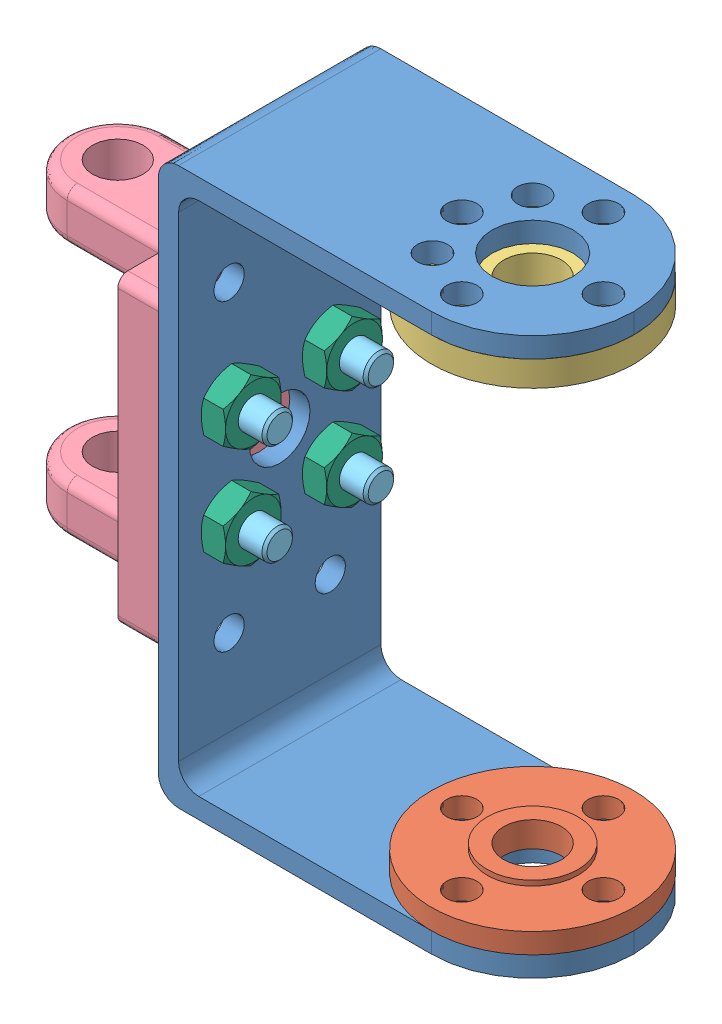
SolidWorks assembly moteur-bras-v2, configuration Défaut. Lengths in mm.
Overall size (56.6 55 20).
12 component instances, 6 part files, 28 mates.
Components (placement in the parent):
- moteur-support-mobile-v2-1: moteur-support-mobile-v2 [Défaut] at (18.386 -2.2808 45) size (37 55 20)
- moteur-platine_libre-1: moteur-platine_libre [Défaut] at (8.386 -27.7808 55) x (1 0 0) z (0 1 0) size (20 20 2.5)
- moteur-platine_moteur-1: moteur-platine_moteur [Défaut] at (8.386 23.2192 55) x (1 0 0) z (0 -1 0) size (20 20 4.5)
- support-fourchette-chc_m3-1: support-fourchette-chc_m3 [Défaut] at (-32.614 -2.2808 55) x (0 1 0) z (0 0 1) size (30 19.6 20)
- vis-chc-1: vis-chc [Vis CHC M3x8] at (-19.614 2.7192 50) x (0 0.164744 0.986336) z (0 -0.986336 0.164744) size (5.5 11 5.5)
- ecrou-h-1: ecrou-h [6012 HU M3] at (-16.614 2.7192 50) x (0 0.866025 0.5) z (0 -0.5 0.866025) size (5.5 2.4 6.35)
- ecrou-h-2: ecrou-h [6012 HU M3] at (-14.214 2.7192 60) x (0 -0.866025 -0.5) z (0 -0.5 0.866025) size (5.5 2.4 6.35)
- ecrou-h-3: ecrou-h [6012 HU M3] at (-14.214 -7.2808 50) x (0 -0.866025 -0.5) z (0 -0.5 0.866025) size (5.5 2.4 6.35)
- ecrou-h-4: ecrou-h [6012 HU M3] at (-14.214 -7.2808 60) x (0 -0.866025 -0.5) z (0 -0.5 0.866025) size (5.5 2.4 6.35)
- vis-chc-2: vis-chc [Vis CHC M3x8] at (-19.614 2.7192 60) x (0 -0.933966 -0.357361) z (0 0.357361 -0.933966) size (5.5 11 5.5)
- vis-chc-3: vis-chc [Vis CHC M3x8] at (-19.614 -7.2808 60) x (0 0.351541 0.936173) z (0 -0.936173 0.351541) size (5.5 11 5.5)
- vis-chc-4: vis-chc [Vis CHC M3x8] at (-19.614 -7.2808 50) x (0 -0.47591 0.879494) z (0 -0.879494 -0.47591) size (5.5 11 5.5)
Mates (geometry in assembly coordinates):
- Coïncidente1: coincident anti-aligned: plane of moteur-support-mobile-v2-1 through (-14.614 23.2192 65) normal (0 -1 0); plane of moteur-platine_moteur-1 through (8.386 23.2192 55) normal (0 1 0)
- Coïncidente2: coincident anti-aligned: plane of moteur-support-mobile-v2-1 through (18.386 -27.7808 65) normal (0 1 0); plane of moteur-platine_libre-1 through (8.386 -27.7808 55) normal (0 -1 0)
- Coaxiale1: concentric aligned: cylinder of moteur-support-mobile-v2-1 through (1.386 -29.7808 55) axis (0 1 0) radius 1.5; cylinder of moteur-platine_libre-1 through (1.386 -27.7808 55) axis (0 1 0) radius 1.5
- Coaxiale2: concentric anti-aligned: cylinder of moteur-support-mobile-v2-1 through (8.386 -29.7808 55) axis (0 1 0) radius 4; cylinder of moteur-platine_libre-1 through (8.386 -25.7808 55) axis (0 -1 0) radius 2.85
- Coaxiale3: concentric aligned: cylinder of moteur-support-mobile-v2-1 through (8.386 -29.7808 55) axis (0 1 0) radius 4; cylinder of moteur-platine_moteur-1 through (8.386 20.7192 55) axis (0 1 0) radius 2.85
- Coaxiale4: concentric anti-aligned: cylinder of moteur-support-mobile-v2-1 through (8.386 -29.7808 62) axis (0 1 0) radius 1.5; cylinder of moteur-platine_moteur-1 through (8.386 23.2192 62) axis (0 -1 0) radius 1.5
- Coïncidente3: coincident anti-aligned: plane of moteur-support-mobile-v2-1 through (-18.614 23.2192 65) normal (-1 0 0); plane of support-fourchette-chc_m3-1 through (-18.614 -2.2808 55) normal (1 0 0)
- Coaxiale5: concentric aligned: cylinder of moteur-support-mobile-v2-1 through (18.387 2.7192 50) axis (-1 0 0) radius 1.5; cylinder of support-fourchette-chc_m3-1 through (-18.613 2.7192 50) axis (-1 0 0) radius 1.6
- Coaxiale6: concentric aligned: cylinder of support-fourchette-chc_m3-1 through (-18.613 2.7192 50) axis (-1 0 0) radius 1.6; cylinder of vis-chc-m2-1 through (-11.614 2.7192 50) axis (-1 0 0) radius 1.5
- Coïncidente4: coincident anti-aligned: plane of moteur-support-mobile-v2-1 through (-16.614 -25.7808 65) normal (1 0 0); plane of ecrou-h-m2-1 through (-16.614 5.8946 50) normal (-1 0 0)
- Coaxiale7: concentric aligned: cylinder of moteur-support-mobile-v2-1 through (18.387 2.7192 50) axis (-1 0 0) radius 1.5; cylinder of ecrou-h-m2-1 through (-14.214 2.7192 50) axis (-1 0 0) radius 1.2295
- Parallèle1: parallel aligned: plane of moteur-support-mobile-v2-1 through (-16.614 23.2192 45) normal (0 0 -1); plane of ecrou-h-m2-1 through (-14.214 4.3069 47.25) normal (0 0 -1)
- Coaxiale8: concentric aligned: cylinder of moteur-support-mobile-v2-1 through (18.387 2.7192 60) axis (-1 0 0) radius 1.5; cylinder of vis-chc-2 through (-11.614 2.7192 60) axis (-1 0 0) radius 1.5
- Coaxiale9: concentric aligned: cylinder of moteur-support-mobile-v2-1 through (18.387 -7.2808 60) axis (-1 0 0) radius 1.5; cylinder of vis-chc-3 through (-11.614 -7.2808 60) axis (-1 0 0) radius 1.5
- Coaxiale10: concentric aligned: cylinder of moteur-support-mobile-v2-1 through (18.387 -7.2808 50) axis (-1 0 0) radius 1.5; cylinder of vis-chc-4 through (-11.614 -7.2808 50) axis (-1 0 0) radius 1.5
- Coïncidente8: coincident anti-aligned: plane of support-fourchette-chc_m3-1 through (-19.614 2.7192 50) normal (-1 0 0); plane of vis-chc-1 through (-19.614 2.7192 50) normal (1 0 0)
- Coïncidente9: coincident anti-aligned: plane of support-fourchette-chc_m3-1 through (-19.614 2.7192 60) normal (-1 0 0); plane of vis-chc-2 through (-19.614 2.7192 60) normal (1 0 0)
- Coïncidente10: coincident anti-aligned: plane of support-fourchette-chc_m3-1 through (-19.614 -7.2808 60) normal (-1 0 0); plane of vis-chc-3 through (-19.614 -7.2808 60) normal (1 0 0)
- Coïncidente11: coincident anti-aligned: plane of support-fourchette-chc_m3-1 through (-19.614 -7.2808 50) normal (-1 0 0); plane of vis-chc-4 through (-19.614 -7.2808 50) normal (1 0 0)
- Coaxiale11: concentric anti-aligned: cylinder of ecrou-h-2 through (-16.614 2.7192 60) axis (1 0 0) radius 1.2295; cylinder of vis-chc-2 through (-11.614 2.7192 60) axis (-1 0 0) radius 1.5
- Coaxiale12: concentric anti-aligned: cylinder of ecrou-h-3 through (-16.614 -7.2808 50) axis (1 0 0) radius 1.2295; cylinder of vis-chc-4 through (-11.614 -7.2808 50) axis (-1 0 0) radius 1.5
- Coaxiale13: concentric anti-aligned: cylinder of ecrou-h-4 through (-16.614 -7.2808 60) axis (1 0 0) radius 1.2295; cylinder of vis-chc-3 through (-11.614 -7.2808 60) axis (-1 0 0) radius 1.5
- Coïncidente12: coincident anti-aligned: plane of moteur-support-mobile-v2-1 through (-16.614 -25.7808 65) normal (1 0 0); plane of ecrou-h-4 through (-16.614 -8.8685 57.25) normal (-1 0 0)
- Coïncidente13: coincident anti-aligned: plane of moteur-support-mobile-v2-1 through (-16.614 -25.7808 65) normal (1 0 0); plane of ecrou-h-3 through (-16.614 -8.8685 47.25) normal (-1 0 0)
- Coïncidente14: coincident anti-aligned: plane of moteur-support-mobile-v2-1 through (-16.614 -25.7808 65) normal (1 0 0); plane of ecrou-h-2 through (-16.614 1.1315 57.25) normal (-1 0 0)
- Parallèle2: parallel aligned: plane of moteur-support-mobile-v2-1 through (-16.614 23.2192 65) normal (0 0 1); plane of ecrou-h-2 through (-16.614 4.3069 62.75) normal (0 0 1)
- Parallèle3: parallel aligned: plane of moteur-support-mobile-v2-1 through (-16.614 23.2192 65) normal (0 0 1); plane of ecrou-h-4 through (-16.614 -5.6931 62.75) normal (0 0 1)
- Parallèle4: parallel aligned: plane of moteur-support-mobile-v2-1 through (-16.614 23.2192 45) normal (0 0 -1); plane of ecrou-h-3 through (-16.614 -8.8685 47.25) normal (0 0 -1)
